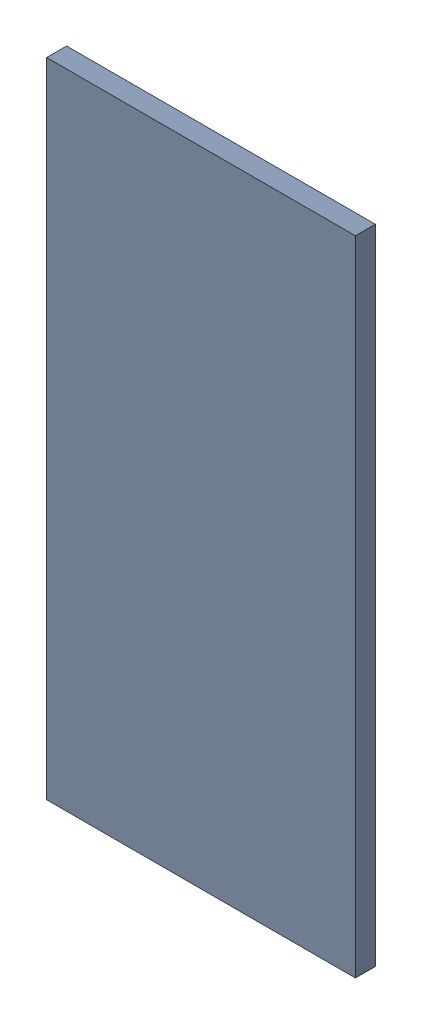
SolidWorks assembly Pad ADXL345-4(20.6mm,58.097mm) on Top Layer, configuration Predeterminado. Lengths in mm.
Overall size (0.55 1.15 0.04).
2 component instances, 1 part files, 0 mates.
Components (placement in the parent):
- Pad ADXL345-4(20.6mm,58.097mm) on Top Layer-1-1: Pad ADXL345-4(20.6mm,58.097mm) on Top Layer-1 [Predeterminado] at (-68.317 -44.187 -0.0457) size (0.55 1.15 0.04)
  - Pad ADXL345-4(20.6mm,58.097mm) on Top Layer-Part-1-1: Pad ADXL345-4(20.6mm,58.097mm) on Top Layer-Part-1 [Predeterminado] at origin size (0.55 1.15 0.04)
